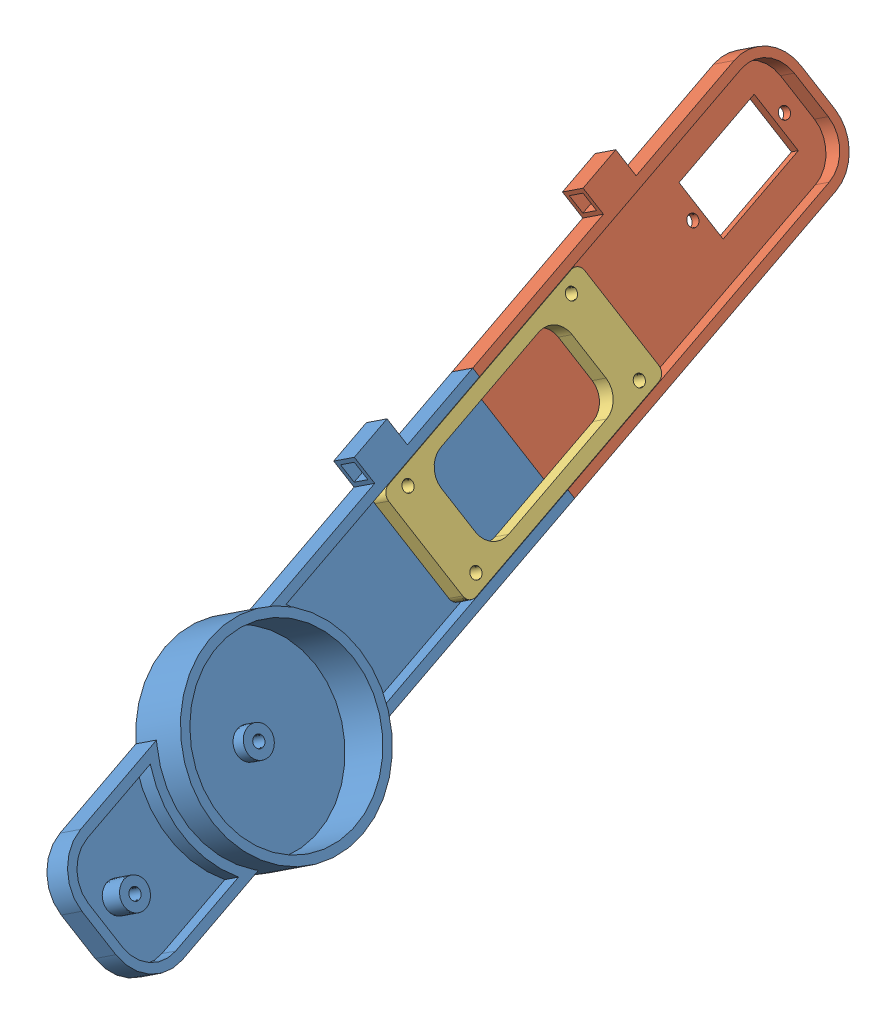
SolidWorks assembly Złożenie4, configuration Domyślna. Lengths in mm.
Overall size (69.67 92.42 221.23).
4 component instances, 4 part files, 9 mates.
Components (placement in the parent):
- ramie2-1: ramie2 [Domyślna] at (123.8039 -213.4319 234.5334) x (-0.163325 0.247449 -0.955036) z (0.834596 0.550863 0) size (130 45 13)
- ramie21-1: ramie21 [Domyślna] at (123.8039 -213.4319 234.5334) x (-0.163325 0.247449 -0.955036) z (0.834596 0.550863 0) size (90 36 6)
- plytka2-1: plytka2 [Domyślna] at (115.7455 -190.3308 158.1305) x (-0.526093 0.797069 0.29649) z (-0.834596 -0.550863 0) size (25.8 60 4)
- servo TOWER PRO 9g SG90-1: servo TOWER PRO 9g SG90 [Défaut] at (85.975 -182.4408 103.4882) x (0.163325 -0.247449 0.955036) z (0.834596 0.550863 0) size (32 11.7 29.7) (hidden)
Mates (geometry in assembly coordinates):
- Wspólnie167: coincident anti-aligned: plane of ramie2-1 through (110.7379 -193.636 158.1305) normal (-0.163325 0.247449 -0.955036); plane of ramie21-1 through (110.7379 -193.636 158.1305) normal (0.163325 -0.247449 0.955036)
- Wspólnie168: coincident aligned: plane of ramie2-1 through (129.0863 -210.5432 286.7325) normal (-0.526093 0.797069 0.29649); plane of ramie21-1 through (129.0863 -210.5432 286.7325) normal (-0.526093 0.797069 0.29649)
- Wspólnie169: coincident aligned: plane of ramie2-1 through (123.8039 -213.4319 234.5334) normal (-0.834596 -0.550863 0); plane of ramie21-1 through (123.8039 -213.4319 234.5334) normal (-0.834596 -0.550863 0)
- Koncentryczne207: concentric anti-aligned: cylinder of ramie2-1 through (121.7511 -206.6912 179.0415) axis (0.834596 0.550863 0) radius 1.2; cylinder of plytka2-1 through (121.7511 -206.6912 179.0415) axis (-0.834596 -0.550863 0) radius 1.3
- Koncentryczne208: concentric anti-aligned: cylinder of ramie2-1 through (111.2293 -190.7498 184.9713) axis (0.834596 0.550863 0) radius 1.2; cylinder of plytka2-1 through (111.2293 -190.7498 184.9713) axis (-0.834596 -0.550863 0) radius 1.3
- Wspólnie248: coincident anti-aligned: plane of ramie2-1 through (125.4731 -212.3302 234.5334) normal (0.834596 0.550863 0); plane of servo TOWER PRO 9g SG90-1 through (99.7458 -173.3516 103.4882) normal (-0.834596 -0.550863 0)
- Wspólnie183: coincident anti-aligned: plane of ramie21-1 through (125.4731 -212.3302 234.5334) normal (0.834596 0.550863 0); plane of plytka2-1 through (112.4071 -192.5342 158.1305) normal (-0.834596 -0.550863 0)
- Koncentryczne265: concentric aligned: circle of ramie21-1; cylinder of servo TOWER PRO 9g SG90-1 through (84.9169 -180.8377 77.9075) axis (0.834596 0.550863 0) radius 1.25
- Koncentryczne266: concentric aligned: circle of ramie21-1; cylinder of servo TOWER PRO 9g SG90-1 through (89.49 -187.7663 104.6485) axis (0.834596 0.550863 0) radius 1.25
